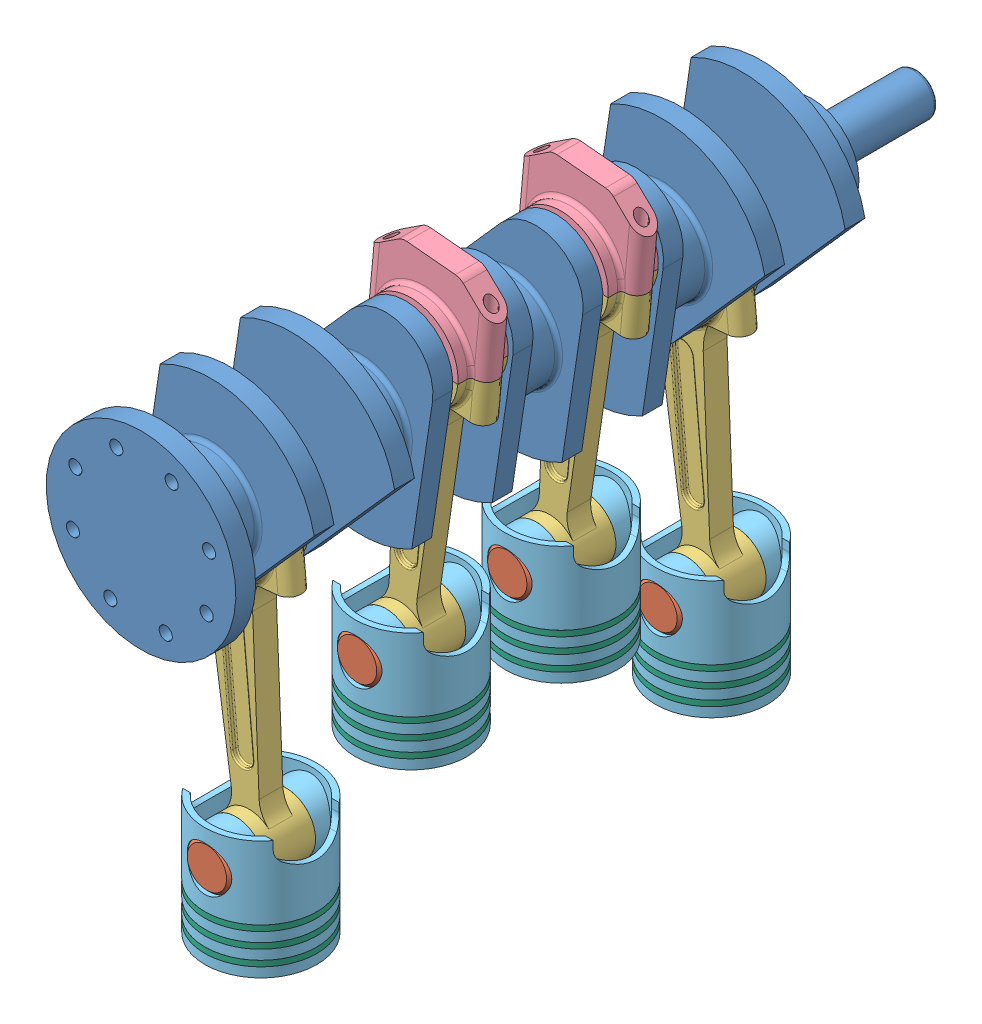
SolidWorks assembly Assembly, configuration Default. Lengths in mm.
Overall size (198.18 412.16 589).
29 component instances, 6 part files, 66 mates.
Components (placement in the parent):
- Crankshaft-1: Crankshaft [Default] at (0 316.357 16936.5514) x (0.906038 -0.423195 0) z (0 0 1) size (144 160 589)
- Piston Pin-1: Piston Pin [Default] at (0 76.1548 16974.5514) x (1 0 0) z (0 1 0) size (33.8 82 33.8)
- Connecting Rod-1: Connecting Rod [Default] at (0 76.1548 16974.5514) x (-0.995708 -0.092548 0) z (0 0 1) size (94 223.7 38)
- Connecting Rod Cap-1: Connecting Rod Cap [Default] at (-18.6206 276.4913 16974.5514) x (-0.995708 -0.092548 0) z (0 0 1) size (94 60 38)
- Piston-1: Piston [Default] at (0 103.1548 16974.5514) x (-1 0 0) z (0 0 1) size (85 95 85)
- Piston Ring-1: Piston Ring [Default] at (0 24.7548 16974.5514) x (-0.999982 0 -0.00596) z (-0.00596 0 0.999982) size (85 4.3 85)
- Piston Ring-7: Piston Ring [Default] at (0 36.3548 16974.5514) x (-0.982082 0 -0.188455) z (-0.188455 0 0.982082) size (85 4.3 85)
- Piston Ring-11: Piston Ring [Default] at (0 47.9548 16974.5514) x (-0.896643 0 -0.442755) z (-0.442755 0 0.896643) size (85 4.3 85)
- Piston Ring-28: Piston Ring [Default] at (0 127.6862 17088.5514) x (-0.96064 0 -0.277796) z (-0.277796 0 0.96064) size (85 4.3 85)
- Piston Ring-29: Piston Ring [Default] at (0 116.0862 17088.5514) x (-0.999923 0 -0.012418) z (-0.012418 0 0.999923) size (85 4.3 85)
- Piston-7: Piston [Default] at (0 182.8862 17088.5514) x (-1 0 0) z (0 0 1) size (85 95 85)
- Piston Pin-7: Piston Pin [Default] at (0 155.8862 17088.5514) x (0.987351 0.158553 0) z (-0.158553 0.987351 0) size (33.8 82 33.8)
- Piston Ring-30: Piston Ring [Default] at (0 104.4862 17088.5514) x (-0.985379 0 0.170374) z (0.170374 0 0.985379) size (85 4.3 85)
- Connecting Rod-7: Connecting Rod [Default] at (0 155.8862 17088.5514) x (-0.995708 0.092548 0) z (0 0 1) size (94 223.7 38)
- Connecting Rod Cap-7: Connecting Rod Cap [Default] at (18.6206 356.2227 17088.5514) x (-0.995708 0.092548 0) z (0 0 1) size (94 60 38)
- Piston Ring-34: Piston Ring [Default] at (0 127.6862 17202.5514) x (-0.99603 0 -0.089015) z (-0.089015 0 0.99603) size (85 4.3 85)
- Piston Ring-35: Piston Ring [Default] at (0 116.0862 17202.5514) x (-0.983853 0 0.178977) z (0.178977 0 0.983853) size (85 4.3 85)
- Piston-9: Piston [Default] at (0 182.8862 17202.5514) x (1 0 0) z (0 0 -1) size (85 95 85)
- Piston Pin-9: Piston Pin [Default] at (0 155.8862 17202.5514) x (0.994367 0.105992 0) z (0.105992 -0.994367 0) size (33.8 82 33.8)
- Piston Ring-36: Piston Ring [Default] at (0 104.4862 17202.5514) x (-0.934631 0 0.355618) z (0.355618 0 0.934631) size (85 4.3 85)
- Connecting Rod-9: Connecting Rod [Default] at (0 155.8862 17202.5514) x (0.995708 -0.092548 0) z (0 0 -1) size (94 223.7 38)
- Connecting Rod Cap-9: Connecting Rod Cap [Default] at (18.6206 356.2227 17202.5514) x (0.995708 -0.092548 0) z (0 0 -1) size (94 60 38)
- Piston Ring-40: Piston Ring [Default] at (0 47.9548 17316.5514) x (-0.991648 0 0.128974) z (0.128974 0 0.991648) size (85 4.3 85)
- Piston Ring-41: Piston Ring [Default] at (0 36.3548 17316.5514) x (-0.921677 0 0.387957) z (0.387957 0 0.921677) size (85 4.3 85)
- Piston-11: Piston [Default] at (0 103.1548 17316.5514) x (1 0 0) z (0 0 -1) size (85 95 85)
- Piston Pin-11: Piston Pin [Default] at (0 76.1548 17316.5514) x (0.999918 0.012843 0) z (0.012843 -0.999918 0) size (33.8 82 33.8)
- Piston Ring-42: Piston Ring [Default] at (0 24.7548 17316.5514) x (-0.835342 0 0.549731) z (0.549731 0 0.835342) size (85 4.3 85)
- Connecting Rod-11: Connecting Rod [Default] at (0 76.1548 17316.5514) x (0.995708 0.092548 0) z (0 0 -1) size (94 223.7 38)
- Connecting Rod Cap-11: Connecting Rod Cap [Default] at (-18.6206 276.4913 17316.5514) x (0.995708 0.092548 0) z (0 0 -1) size (94 60 38)
Mates (geometry in assembly coordinates):
- Concentric1: concentric: cylinder of assembly; cylinder of Crankshaft-1 through (0 316.357 16464.5514) axis (0 0 1) radius 16; line of assembly
- Coincident2: coincident: plane of Connecting Rod-1 through (0 76.1548 16620.5514) normal (0 0 1); plane of Piston-1 through (0 103.1548 16620.5514) normal (0 0 1)
- Concentric2: concentric: cylinder of Connecting Rod-1 through (0 76.1548 16639.5514) axis (0 0 -1) radius 16.9; cylinder of Piston-1 through (0 76.1548 16578.0514) axis (0 0 1) radius 16.9
- Coincident3: coincident: plane of Piston Pin-1 through (0 76.1548 16620.5514) normal (0 0 -1); plane of Piston-1 through (0 103.1548 16620.5514) normal (0 0 1)
- Concentric3: concentric: cylinder of Piston Pin-1 through (0 76.1548 16579.5514) axis (0 0 1) radius 16.9; cylinder of Piston-1 through (0 76.1548 16578.0514) axis (0 0 1) radius 16.9
- Coincident4: coincident: plane of Piston-1 through (0 24.7548 16620.5514) normal (0 -1 0); plane of Piston Ring-1 through (0 24.7548 16620.5514) normal (0 1 0)
- Concentric4: concentric: cylinder of Piston-1 through (0 24.7548 16620.5514) axis (0 -1 0) radius 39.5; cylinder of Piston Ring-1 through (0 20.4548 16620.5514) axis (0 1 0) radius 42.5
- Coincident8: coincident: circle of Piston-1; plane of Piston Ring-7 through (0 36.3548 16620.5514) normal (0 1 0)
- Concentric8: concentric: cylinder of Piston-1 through (0 36.3548 16620.5514) axis (0 -1 0) radius 39.5; cylinder of Piston Ring-7 through (0 32.0548 16620.5514) axis (0 1 0) radius 42.5
- Coincident9: coincident: plane of Piston-1 through (0 47.9548 16620.5514) normal (0 -1 0); plane of Piston Ring-11 through (0 47.9548 16620.5514) normal (0 1 0)
- Concentric9: concentric: cylinder of Piston-1 through (0 47.9548 16620.5514) axis (0 -1 0) radius 39.5; cylinder of Piston Ring-11 through (0 43.6548 16620.5514) axis (0 1 0) radius 42.5
- Coincident10: coincident: circle of Connecting Rod-1; circle of Connecting Rod Cap-1
- Width1: width: plane of Crankshaft-1 through (0 316.357 16643.5514) normal (0 0 -1); plane of Connecting Rod-1 through (0 316.357 16597.5514) normal (0 0 1); plane of Crankshaft-1 through (0 76.1548 16629.5514) normal (0 0 1); plane of Connecting Rod-1 through (0 76.1548 16611.5514) normal (0 0 -1)
- Concentric10: concentric: cylinder of Crankshaft-1 through (-18.6206 276.4913 16643.5514) axis (0 0 -1) radius 27; cylinder of Connecting Rod Cap-1 through (-18.6206 276.4913 16639.5514) axis (0 0 -1) radius 27
- Coincident16: coincident: plane of assembly; plane of Crankshaft-1 through (0 316.357 16464.5514) normal (0 0 -1); point of assembly
- Concentric14: concentric: cylinder of assembly; cylinder of Piston-1 through (0 13.1548 16620.5514) axis (0 1 0) radius 42.5; line of assembly
- Concentric47: concentric: cylinder of Connecting Rod-1 through (19.2163 280.0082 16620.5514) axis (0.092548 -0.995708 0) radius 4.5; cylinder of Connecting Rod Cap-1 through (13.6634 339.7516 16620.5514) axis (0.092548 -0.995708 0) radius 4.5
- Concentric48: concentric: cylinder of Connecting Rod-1 through (-56.4575 272.9745 16620.5514) axis (0.092548 -0.995708 0) radius 4.5; cylinder of Connecting Rod Cap-1 through (-62.0105 332.718 16620.5514) axis (0.092548 -0.995708 0) radius 4.5
- Coincident49: coincident: plane of Piston-7 through (0 182.8862 16734.5514) normal (0 0 1); plane of Connecting Rod-7 through (0 155.8862 16734.5514) normal (0 0 1)
- Concentric49: concentric: cylinder of Piston-7 through (0 155.8862 16692.0514) axis (0 0 1) radius 16.9; cylinder of Connecting Rod-7 through (0 155.8862 16753.5514) axis (0 0 -1) radius 16.9
- Coincident50: coincident: plane of Piston-7 through (0 182.8862 16734.5514) normal (0 0 1); plane of Piston Pin-7 through (0 155.8862 16734.5514) normal (0 0 -1)
- Concentric50: concentric: cylinder of Piston-7 through (0 155.8862 16692.0514) axis (0 0 1) radius 16.9; cylinder of Piston Pin-7 through (0 155.8862 16693.5514) axis (0 0 1) radius 16.9
- Coincident51: coincident: plane of Piston-7 through (0 104.4862 16734.5514) normal (0 -1 0); plane of Piston Ring-30 through (0 104.4862 16734.5514) normal (0 1 0)
- Concentric51: concentric: cylinder of Piston-7 through (0 104.4862 16734.5514) axis (0 -1 0) radius 39.5; cylinder of Piston Ring-30 through (0 100.1862 16734.5514) axis (0 1 0) radius 42.5
- Coincident52: coincident: plane of Piston Ring-29 through (0 116.0862 16734.5514) normal (0 1 0); circle of Piston-7
- Concentric52: concentric: cylinder of Piston Ring-29 through (0 111.7862 16734.5514) axis (0 1 0) radius 42.5; cylinder of Piston-7 through (0 116.0862 16734.5514) axis (0 -1 0) radius 39.5
- Coincident53: coincident: plane of Piston Ring-28 through (0 127.6862 16734.5514) normal (0 1 0); plane of Piston-7 through (0 127.6862 16734.5514) normal (0 -1 0)
- Concentric53: concentric: cylinder of Piston Ring-28 through (0 123.3862 16734.5514) axis (0 1 0) radius 42.5; cylinder of Piston-7 through (0 127.6862 16734.5514) axis (0 -1 0) radius 39.5
- Coincident54: coincident: circle of Connecting Rod-7; circle of Connecting Rod Cap-7
- Concentric54: concentric: cylinder of Connecting Rod-7 through (56.4575 352.7059 16734.5514) axis (-0.092548 -0.995708 0) radius 4.5; cylinder of Connecting Rod Cap-7 through (62.0105 412.4494 16734.5514) axis (-0.092548 -0.995708 0) radius 4.5
- Concentric55: concentric: cylinder of Connecting Rod-7 through (-19.2163 359.7395 16734.5514) axis (-0.092548 -0.995708 0) radius 4.5; cylinder of Connecting Rod Cap-7 through (-13.6634 419.483 16734.5514) axis (-0.092548 -0.995708 0) radius 4.5
- Width5: width: plane of Crankshaft-1 through (0 316.357 16757.5514) normal (0 0 -1); plane of Connecting Rod-7 through (0 316.357 16711.5514) normal (0 0 1); plane of Crankshaft-1 through (0 155.8862 16743.5514) normal (0 0 1); plane of Connecting Rod-7 through (0 155.8862 16725.5514) normal (0 0 -1)
- Concentric56: concentric: cylinder of Crankshaft-1 through (18.6206 356.2227 16757.5514) axis (0 0 -1) radius 27; cylinder of Connecting Rod Cap-7 through (18.6206 356.2227 16753.5514) axis (0 0 -1) radius 27
- Concentric57: concentric: cylinder of assembly; cylinder of Piston-7 through (0 92.8862 16734.5514) axis (0 1 0) radius 42.5; line of assembly
- Coincident61: coincident: plane of Piston-9 through (0 182.8862 16848.5514) normal (0 0 -1); plane of Connecting Rod-9 through (0 155.8862 16848.5514) normal (0 0 -1)
- Concentric65: concentric: cylinder of Piston-9 through (0 155.8862 16891.0514) axis (0 0 -1) radius 16.9; cylinder of Connecting Rod-9 through (0 155.8862 16829.5514) axis (0 0 1) radius 16.9
- Coincident62: coincident: plane of Piston-9 through (0 182.8862 16848.5514) normal (0 0 -1); plane of Piston Pin-9 through (0 155.8862 16848.5514) normal (0 0 1)
- Concentric66: concentric: cylinder of Piston-9 through (0 155.8862 16891.0514) axis (0 0 -1) radius 16.9; cylinder of Piston Pin-9 through (0 155.8862 16889.5514) axis (0 0 -1) radius 16.9
- Coincident63: coincident: plane of Piston-9 through (0 104.4862 16848.5514) normal (0 -1 0); plane of Piston Ring-36 through (0 104.4862 16848.5514) normal (0 1 0)
- Concentric67: concentric: cylinder of Piston-9 through (0 104.4862 16848.5514) axis (0 -1 0) radius 39.5; cylinder of Piston Ring-36 through (0 100.1862 16848.5514) axis (0 1 0) radius 42.5
- Coincident64: coincident: plane of Piston Ring-35 through (0 116.0862 16848.5514) normal (0 1 0); circle of Piston-9
- Concentric68: concentric: cylinder of Piston Ring-35 through (0 111.7862 16848.5514) axis (0 1 0) radius 42.5; cylinder of Piston-9 through (0 116.0862 16848.5514) axis (0 -1 0) radius 39.5
- Coincident65: coincident: plane of Piston Ring-34 through (0 127.6862 16848.5514) normal (0 1 0); plane of Piston-9 through (0 127.6862 16848.5514) normal (0 -1 0)
- Concentric69: concentric: cylinder of Piston Ring-34 through (0 123.3862 16848.5514) axis (0 1 0) radius 42.5; cylinder of Piston-9 through (0 127.6862 16848.5514) axis (0 -1 0) radius 39.5
- Coincident66: coincident: circle of Connecting Rod-9; circle of Connecting Rod Cap-9
- Concentric70: concentric: cylinder of Connecting Rod-9 through (-19.2163 359.7395 16848.5514) axis (-0.092548 -0.995708 0) radius 4.5; cylinder of Connecting Rod Cap-9 through (-13.6634 419.483 16848.5514) axis (-0.092548 -0.995708 0) radius 4.5
- Concentric71: concentric: cylinder of Connecting Rod-9 through (56.4575 352.7059 16848.5514) axis (-0.092548 -0.995708 0) radius 4.5; cylinder of Connecting Rod Cap-9 through (62.0105 412.4494 16848.5514) axis (-0.092548 -0.995708 0) radius 4.5
- Width6: width: plane of Crankshaft-1 through (0 316.357 16871.5514) normal (0 0 -1); plane of Connecting Rod-9 through (0 316.357 16825.5514) normal (0 0 1); plane of Crankshaft-1 through (0 155.8862 16839.5514) normal (0 0 -1); plane of Connecting Rod-9 through (0 155.8862 16857.5514) normal (0 0 1)
- Concentric72: concentric: cylinder of Crankshaft-1 through (18.6206 356.2227 16825.5514) axis (0 0 1) radius 27; cylinder of Connecting Rod Cap-9 through (18.6206 356.2227 16829.5514) axis (0 0 1) radius 27
- Concentric73: concentric: cylinder of assembly; cylinder of Piston-9 through (0 92.8862 16848.5514) axis (0 1 0) radius 42.5; line of assembly
- Coincident73: coincident: plane of Piston-11 through (0 103.1548 16962.5514) normal (0 0 -1); plane of Connecting Rod-11 through (0 76.1548 16962.5514) normal (0 0 -1)
- Concentric81: concentric: cylinder of Piston-11 through (0 76.1548 17005.0514) axis (0 0 -1) radius 16.9; cylinder of Connecting Rod-11 through (0 76.1548 16943.5514) axis (0 0 1) radius 16.9
- Coincident74: coincident: plane of Piston-11 through (0 103.1548 16962.5514) normal (0 0 -1); plane of Piston Pin-11 through (0 76.1548 16962.5514) normal (0 0 1)
- Concentric82: concentric: cylinder of Piston-11 through (0 76.1548 17005.0514) axis (0 0 -1) radius 16.9; cylinder of Piston Pin-11 through (0 76.1548 17003.5514) axis (0 0 -1) radius 16.9
- Coincident75: coincident: plane of Piston-11 through (0 24.7548 16962.5514) normal (0 -1 0); plane of Piston Ring-42 through (0 24.7548 16962.5514) normal (0 1 0)
- Concentric83: concentric: cylinder of Piston-11 through (0 24.7548 16962.5514) axis (0 -1 0) radius 39.5; cylinder of Piston Ring-42 through (0 20.4548 16962.5514) axis (0 1 0) radius 42.5
- Coincident76: coincident: plane of Piston Ring-41 through (0 36.3548 16962.5514) normal (0 1 0); circle of Piston-11
- Concentric84: concentric: cylinder of Piston Ring-41 through (0 32.0548 16962.5514) axis (0 1 0) radius 42.5; cylinder of Piston-11 through (0 36.3548 16962.5514) axis (0 -1 0) radius 39.5
- Coincident77: coincident: plane of Piston Ring-40 through (0 47.9548 16962.5514) normal (0 1 0); plane of Piston-11 through (0 47.9548 16962.5514) normal (0 -1 0)
- Concentric85: concentric: cylinder of Piston Ring-40 through (0 43.6548 16962.5514) axis (0 1 0) radius 42.5; cylinder of Piston-11 through (0 47.9548 16962.5514) axis (0 -1 0) radius 39.5
- Coincident78: coincident: circle of Connecting Rod-11; circle of Connecting Rod Cap-11
- Concentric86: concentric: cylinder of Connecting Rod-11 through (-56.4575 272.9745 16962.5514) axis (0.092548 -0.995708 0) radius 4.5; cylinder of Connecting Rod Cap-11 through (-62.0105 332.718 16962.5514) axis (0.092548 -0.995708 0) radius 4.5
- Concentric87: concentric: cylinder of Connecting Rod-11 through (19.2163 280.0082 16962.5514) axis (0.092548 -0.995708 0) radius 4.5; cylinder of Connecting Rod Cap-11 through (13.6634 339.7516 16962.5514) axis (0.092548 -0.995708 0) radius 4.5
- Width7: width: plane of Crankshaft-1 through (0 316.357 16985.5514) normal (0 0 -1); plane of Connecting Rod-11 through (0 316.357 16939.5514) normal (0 0 1); plane of Crankshaft-1 through (0 76.1548 16953.5514) normal (0 0 -1); plane of Connecting Rod-11 through (0 76.1548 16971.5514) normal (0 0 1)
- Concentric88: concentric: cylinder of Crankshaft-1 through (-18.6206 276.4913 16939.5514) axis (0 0 1) radius 27; cylinder of Connecting Rod Cap-11 through (-18.6206 276.4913 16943.5514) axis (0 0 1) radius 27
- Concentric89: concentric: cylinder of assembly; cylinder of Piston-11 through (0 13.1548 16962.5514) axis (0 1 0) radius 42.5; line of assembly
